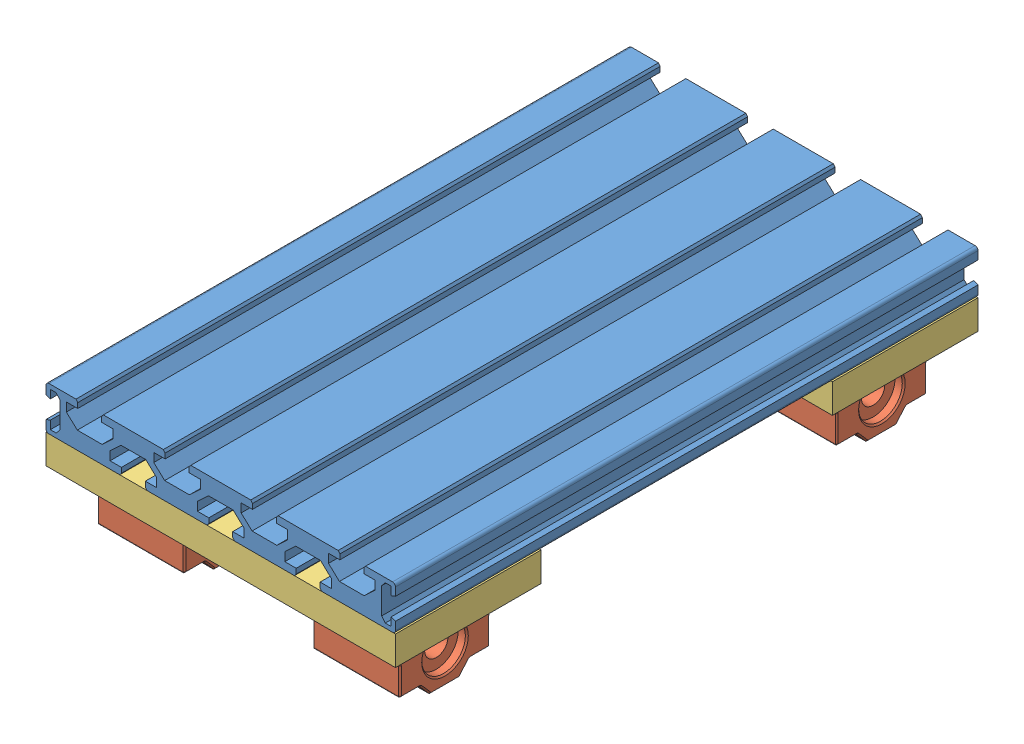
SolidWorks assembly Y_AXIS, configuration Default. Lengths in mm.
Overall size (120 48.46 200).
9 component instances, 5 part files, 32 mates.
Components (placement in the parent):
- surface_profile-1: surface_profile [Varsayılan] at (117.712 66.925 209.3681) x (-1 0 0) z (0 0 1) size (120 15 200)
- linear_bearing_caged-1: linear_bearing_caged [Default] at (94.712 45.925 34.3681) x (0 0 1) z (1 0 0) size (34 22 30)
- linear_bearing_caged-2: linear_bearing_caged [Default] at (94.712 45.925 184.3681) x (0 0 1) z (1 0 0) size (34 22 30)
- linear_bearing_caged-3: linear_bearing_caged [Default] at (20.712 45.925 34.3681) x (0 0 1) z (1 0 0) size (34 22 30)
- linear_bearing_caged-4: linear_bearing_caged [Default] at (20.712 45.925 184.3681) x (0 0 1) z (1 0 0) size (34 22 30)
- y_axis_elevation-1: y_axis_elevation [Default] at (57.712 56.925 184.3681) size (120 10 50)
- y_axis_elevation-2: y_axis_elevation [Default] at (57.712 56.925 34.3681) size (120 10 50)
- trapezoidal_nut-2: trapezoidal_nut [Default] at (46.712 46.925 109.3681) x (0 -0.257243 0.966347) z (1 0 0) size (22 22 15)
- SK10_rod_holder-1: SK10_rod_holder [Default] at (64.712 46.925 109.3681) x (0 0 -1) z (-1 0 0) size (42 32.8 14)
Mates (geometry in assembly coordinates):
- Coincident4: coincident anti-aligned: plane of Part2-1 through (117.712 61.925 209.3681) normal (0 -1 0); plane of linear_bearing_caged-4 through (35.712 56.925 201.3681) normal (0 1 0)
- Coincident5: coincident anti-aligned: plane of Part2-1 through (117.712 61.925 209.3681) normal (0 -1 0); plane of linear_bearing_caged-2 through (109.712 56.925 201.3681) normal (0 1 0)
- Coincident6: coincident anti-aligned: plane of Part2-1 through (117.712 61.925 209.3681) normal (0 -1 0); plane of linear_bearing_caged-3 through (35.712 56.925 51.3681) normal (0 1 0)
- Coincident7: coincident anti-aligned: plane of Part2-1 through (117.712 61.925 209.3681) normal (0 -1 0); plane of linear_bearing_caged-1 through (109.712 56.925 51.3681) normal (0 1 0)
- Coincident8: coincident aligned: plane of linear_bearing_caged-1 through (79.712 45.925 34.3681) normal (-1 0 0); plane of linear_bearing_caged-2 through (79.712 45.925 184.3681) normal (-1 0 0)
- Coincident9: coincident aligned: plane of linear_bearing_caged-3 through (35.712 45.925 34.3681) normal (1 0 0); plane of linear_bearing_caged-4 through (35.712 45.925 184.3681) normal (1 0 0)
- Coincident10: coincident aligned: plane of linear_bearing_caged-1 through (109.712 38.925 18.8681) normal (0 0 -1); plane of linear_bearing_caged-3 through (35.712 38.925 18.8681) normal (0 0 -1)
- Coincident11: coincident aligned: plane of linear_bearing_caged-2 through (109.712 38.925 199.8681) normal (0 0 1); plane of linear_bearing_caged-4 through (35.712 38.925 199.8681) normal (0 0 1)
- Coincident12: coincident anti-aligned: plane of surface_profile-1 through (116.712 66.925 9.3681) normal (0 -1 0); plane of y_axis_elevation-1 through (57.712 66.925 184.3681) normal (0 1 0)
- Coincident13: coincident aligned: plane of surface_profile-1 through (116.712 80.925 209.3681) normal (0 0 1); plane of y_axis_elevation-1 through (117.712 66.925 209.3681) normal (0 0 1)
- Coincident14: coincident aligned: plane of surface_profile-1 through (117.712 70.725 9.3681) normal (1 0 0); plane of y_axis_elevation-1 through (117.712 66.925 209.3681) normal (1 0 0)
- Coincident15: coincident anti-aligned: plane of surface_profile-1 through (116.712 66.925 9.3681) normal (0 -1 0); plane of y_axis_elevation-2 through (57.712 66.925 34.3681) normal (0 1 0)
- Coincident16: coincident aligned: plane of surface_profile-1 through (117.712 70.725 9.3681) normal (1 0 0); plane of y_axis_elevation-2 through (117.712 66.925 59.3681) normal (1 0 0)
- Coincident17: coincident aligned: plane of surface_profile-1 through (116.712 80.925 9.3681) normal (0 0 -1); plane of y_axis_elevation-2 through (117.712 66.925 9.3681) normal (0 0 -1)
- Coincident18: coincident anti-aligned: plane of y_axis_elevation-1 through (57.712 56.925 184.3681) normal (0 -1 0); plane of linear_bearing_caged-4 through (35.712 56.925 201.3681) normal (0 1 0)
- Coincident19: coincident anti-aligned: plane of y_axis_elevation-1 through (57.712 56.925 184.3681) normal (0 -1 0); plane of linear_bearing_caged-2 through (109.712 56.925 201.3681) normal (0 1 0)
- Coincident20: coincident anti-aligned: plane of y_axis_elevation-2 through (57.712 56.925 34.3681) normal (0 -1 0); plane of linear_bearing_caged-1 through (109.712 56.925 51.3681) normal (0 1 0)
- Coincident21: coincident anti-aligned: plane of y_axis_elevation-2 through (57.712 56.925 34.3681) normal (0 -1 0); plane of linear_bearing_caged-3 through (35.712 56.925 51.3681) normal (0 1 0)
- Width1: width anti-aligned: plane of linear_bearing_caged-2 through (109.712 38.925 199.8681) normal (0 0 1); plane of linear_bearing_caged-2 through (109.712 38.925 168.8681) normal (0 0 -1); plane of y_axis_elevation-1 through (117.712 66.925 159.3681) normal (0 0 -1); plane of y_axis_elevation-1 through (117.712 66.925 209.3681) normal (0 0 1)
- Width2: width anti-aligned: plane of linear_bearing_caged-1 through (109.712 38.925 49.8681) normal (0 0 1); plane of linear_bearing_caged-1 through (109.712 38.925 18.8681) normal (0 0 -1); plane of y_axis_elevation-2 through (117.712 66.925 9.3681) normal (0 0 -1); plane of y_axis_elevation-2 through (117.712 66.925 59.3681) normal (0 0 1)
- Width3: width anti-aligned: plane of y_axis_elevation-1 through (117.712 66.925 209.3681) normal (1 0 0); plane of y_axis_elevation-1 through (-2.288 66.925 209.3681) normal (-1 0 0); plane of linear_bearing_caged-4 through (5.712 45.925 184.3681) normal (-1 0 0); plane of linear_bearing_caged-2 through (109.712 45.925 184.3681) normal (1 0 0)
- Distance1: distance = 8 mm aligned: plane of linear_bearing_caged-2 through (109.712 45.925 184.3681) normal (1 0 0); plane of y_axis_elevation-1 through (117.712 66.925 209.3681) normal (1 0 0)
- Concentric2: concentric aligned: cylinder of Y_axis_nut_holder-1 through (65.212 50.525 109.3681) axis (-1 0 0) radius 5.15; cylinder of trapezoidal_nut-1 through (65.212 50.525 109.3681) axis (-1 0 0) radius 5.15
- Coincident24: coincident anti-aligned: plane of Y_axis_nut_holder-1 through (54.212 50.525 109.3681) normal (-1 0 0); plane of trapezoidal_nut-1 through (54.212 50.525 109.3681) normal (1 0 0)
- Coincident25: coincident anti-aligned: plane of surface_profile-1 through (32.412 66.925 9.3681) normal (0 -1 0); plane of Y_axis_nut_holder-1 through (65.212 66.925 79.3681) normal (0 1 0)
- Width8: width anti-aligned: plane of Y_axis_nut_holder-1 through (50.212 50.525 109.3681) normal (-1 0 0); plane of Y_axis_nut_holder-1 through (65.212 50.525 109.3681) normal (1 0 0); plane of surface_profile-1 through (61.962 75.925 9.3681) normal (-0.682318 -0.731055 0); plane of surface_profile-1 through (49.712 72.425 9.3681) normal (0.682318 -0.731055 0)
- Width9: width aligned: plane of Y_axis_nut_holder-1 through (65.212 58.7595 79.3681) normal (0 0 -1); plane of Y_axis_nut_holder-1 through (65.212 58.7595 139.3681) normal (0 0 1); plane of surface_profile-1 through (116.712 80.925 9.3681) normal (0 0 -1); plane of surface_profile-1 through (116.712 80.925 209.3681) normal (0 0 1)
- Concentric5: concentric anti-aligned: cylinder of trapezoidal_nut-2 through (61.712 46.925 109.3681) axis (-1 0 0) radius 5.15; cylinder of SK10_rod_holder-1 through (50.712 46.925 109.3681) axis (1 0 0) radius 5
- Coincident33: coincident anti-aligned: plane of surface_profile-1 through (32.412 66.925 9.3681) normal (0 -1 0); plane of SK10_rod_holder-1 through (50.712 66.925 130.3681) normal (0 1 0)
- Coincident34: coincident anti-aligned: plane of trapezoidal_nut-2 through (50.712 46.925 109.3681) normal (1 0 0); plane of SK10_rod_holder-1 through (50.712 46.925 109.3681) normal (-1 0 0)
- Width14: width anti-aligned: plane of SK10_rod_holder-1 through (50.712 46.925 109.3681) normal (-1 0 0); plane of surface_profile-1 through (64.712 46.925 109.3681) normal (1 0 0); plane of SK10_rod_holder-1 through (112.962 69.925 9.3681) normal (1 0 0); plane of surface_profile-1 through (2.462 78.925 9.3681) normal (-1 0 0)
- Width15: width aligned: plane of SK10_rod_holder-1 through (50.712 34.125 100.3681) normal (0 0 -1); plane of y_axis_elevation-1 through (50.712 34.125 118.3681) normal (0 0 1); plane of SK10_rod_holder-1 through (117.712 66.925 159.3681) normal (0 0 -1); plane of y_axis_elevation-2 through (117.712 66.925 59.3681) normal (0 0 1)
